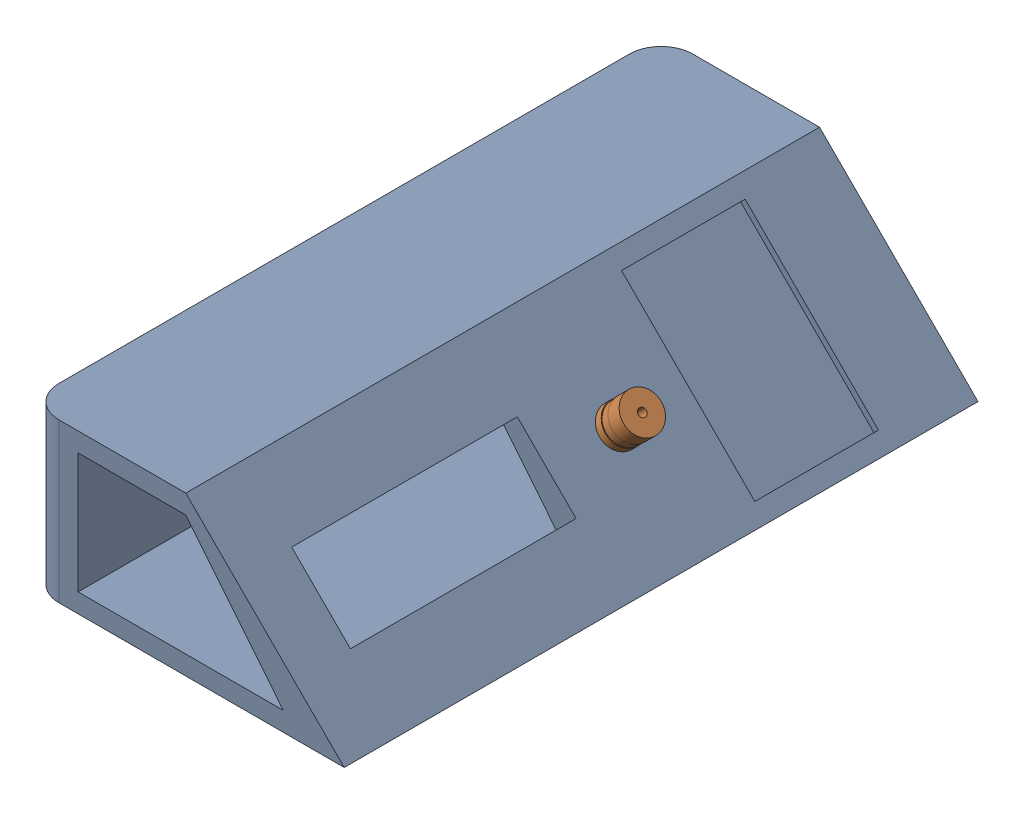
SolidWorks assembly Assem3, configuration Default. Lengths in mm.
Overall size (100 50 200).
2 component instances, 2 part files, 3 mates.
Components (placement in the parent):
- Part3-1: Part3 [Default] at (-58.2054 -5.9348 -108.6228) size (100 50 200)
- buzzer-1: buzzer [Varsayılan] at (24.3041 26.5747 -20.1861) x (0 0 1) z (-0.707107 -0.707107 0) size (11.96 11.96 17.62)
Mates (geometry in assembly coordinates):
- Concentric1: concentric: Part3-1, buzzer-1
- Concentric2: concentric: Part3-1, buzzer-1
- Coincident1: coincident: Part3-1, buzzer-1
